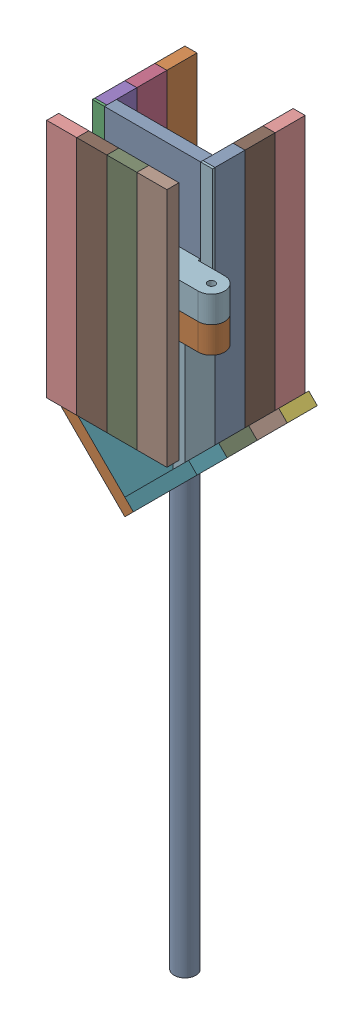
SolidWorks assembly Beach Hut Violet, configuration Défaut. Lengths in mm.
Overall size (132.1 615 113.42).
11 component instances, 11 part files, 0 mates.
Components (placement in the parent):
- Beach hut - Matt-1: Beach hut - Matt [Défaut] at (-308.4913 -626.3682 198.8389) x (-0.87546 0 0.48329) z (-0.48329 0 -0.87546) size (18 500 18)
- Beach hut - Roof 2-1: Beach hut - Roof 2 [Défaut] at (-338.5433 -245.4583 161.3389) x (0 0 1) z (-0.707107 0.707107 0) size (100 10 85)
- Beach hut - Roof 1-1: Beach hut - Roof 1 [Défaut] at (-281.9748 -234.8517 161.3389) x (0 0 1) z (0.707107 0.707107 0) size (100 10 75)
- Beach hut - Wall 1-1: Beach hut - Wall 1 [Défaut] at (-258.4913 -116.3682 161.3389) x (0 0 1) z (0 -1 0) size (100 10 210)
- Beach hut - Wall 2-1: Beach hut - Wall 2 [Défaut] at (-358.4913 -116.3682 161.3389) x (0 0 1) z (0 -1 0) size (100 10 210)
- Beach hut - Wall back-1: Beach hut - Wall back [Défaut] at (-308.4913 -161.3682 148.8389) x (-1 0 0) z (0 0 1) size (80 100 10)
- Beach hut - Wall front-1: Beach hut - Wall front [Défaut] at (-308.4913 -126.3682 238.8389) x (-1 0 0) z (0 0 1) size (80 135 10)
- Beach hut - door-1: Beach hut - door [Défaut] at (-275.9913 -112.3682 248.8389) x (-1 0 0) z (0 1 0) size (100 10 200)
- Beach hut - Door 2-1: Beach hut - Door 2 [Défaut] at (-247.4913 -104.3682 237.8389) x (0 0 1) z (-1 0 0) size (103.42 22 106)
- Beach hut - Wall 3-1: Beach hut - Wall 3 [Défaut] at (-308.4913 -81.3682 215.8389) size (80 70 10)
- Beach hut - Ground-1: Beach hut - Ground [Défaut] at (-308.4913 -104.3682 198.8389) x (-1 0 0) z (0 0 1) size (112 22 100)
